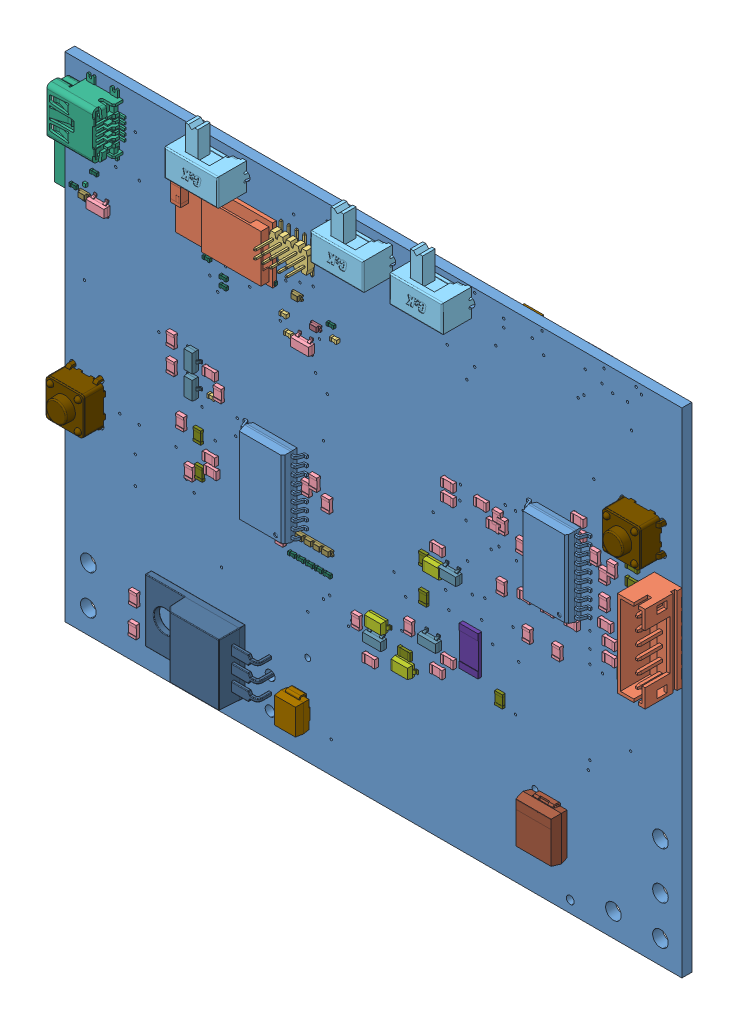
SolidWorks assembly test2, configuration Default. Lengths in mm.
Overall size (103.28 83.92 12.4).
129 component instances, 27 part files, 0 mates.
Components (placement in the parent):
- test2-1: test2 [Default] at origin size (100 80 1.6)
- Header Socket 2_0 6x-1: Header Socket 2_0 6x [Default] at (97.79 46.752 1.6) x (0 -1 0) z (-1 0 0) size (14 8 4.5)
- 0402c_2320560-1: 0402c_2320560 [Default] at (43.9928 61.722 1.6) size (1.15 0.6 0.55)
- 0402c_2320560-2: 0402c_2320560 [Default] at (35.814 61.214 1.6) size (1.15 0.6 0.55)
- 0402c_2320560-3: 0402c_2320560 [Default] at (36.5252 58.8264 1.6) size (1.15 0.6 0.55)
- 0402c_2320560-4: 0402c_2320560 [Default] at (95.123 74.295 0) x (-1 0 0) z (0 0 -1) size (1.15 0.6 0.55)
- 0402c_2320560-5: 0402c_2320560 [Default] at (98.552 77.724 0) x (-1 0 0) z (0 0 -1) size (1.15 0.6 0.55)
- 0402c_2320560-6: 0402c_2320560 [Default] at (78.994 77.978 0) x (-1 0 0) z (0 0 -1) size (1.15 0.6 0.55)
- 0402c_2320560-7: 0402c_2320560 [Default] at (89.916 75.438 0) x (-1 0 0) z (0 0 -1) size (1.15 0.6 0.55)
- 0402c_2320560-8: 0402c_2320560 [Default] at (78.74 74.93 0) x (-1 0 0) z (0 0 -1) size (1.15 0.6 0.55)
- 0402c_2320560-9: 0402c_2320560 [Default] at (90.805 78.232 0) x (-1 0 0) z (0 0 -1) size (1.15 0.6 0.55)
- 0402c_2320560-10: 0402c_2320560 [Default] at (68.58 76.962 0) x (-1 0 0) z (0 0 -1) size (1.15 0.6 0.55)
- 0402c_2320560-11: 0402c_2320560 [Default] at (68.58 78.232 0) x (-1 0 0) z (0 0 -1) size (1.15 0.6 0.55)
- 0402c_2320560-12: 0402c_2320560 [Default] at (68.58 75.438 0) x (-1 0 0) z (0 0 -1) size (1.15 0.6 0.55)
- 0402c_2320560-13: 0402c_2320560 [Default] at (94.488 60.198 0) x (-1 0 0) z (0 0 -1) size (1.15 0.6 0.55)
- 0402c_2320560-14: 0402c_2320560 [Default] at (24.13 43.815 1.6) size (1.15 0.6 0.55)
- 0805-1: 0805 [Default] at (89.0295 53.086 1.6) x (0 -1 0) z (-1 0 0) size (2.03 0.61 1.28)
- 0805-2: 0805 [Default] at (87.7545 49.53 1.6) x (0 1 0) z (1 0 0) size (2.03 0.61 1.28)
- 0805-3: 0805 [Default] at (87.7545 45.72 1.6) x (0 1 0) z (1 0 0) size (2.03 0.61 1.28)
- 0805-4: 0805 [Default] at (86.9696 43.7413 1.6) x (1 0 0) z (0 -1 0) size (2.03 0.61 1.28)
- 0805-5: 0805 [Default] at (87.63 41.5315 1.6) x (1 0 0) z (0 -1 0) size (2.03 0.61 1.28)
- 0805-6: 0805 [Default] at (86.2355 53.4416 1.6) x (0 -1 0) z (-1 0 0) size (2.03 0.61 1.28)
- 0805-7: 0805 [Default] at (77.724 41.2775 1.6) x (1 0 0) z (0 -1 0) size (2.03 0.61 1.28)
- 0805-8: 0805 [Default] at (73.914 41.2775 1.6) x (1 0 0) z (0 -1 0) size (2.03 0.61 1.28)
- 0805-9: 0805 [Default] at (81.534 41.2775 1.6) x (1 0 0) z (0 -1 0) size (2.03 0.61 1.28)
- 0805-10: 0805 [Default] at (82.55 54.2315 1.6) x (1 0 0) z (0 -1 0) size (2.03 0.61 1.28)
- 0805-11: 0805 [Default] at (74.2925 46.99 1.6) x (0 1 0) z (1 0 0) size (2.03 0.61 1.28)
- 0805-12: 0805 [Default] at (71.1225 41.656 1.6) x (0 -1 0) z (-1 0 0) size (2.03 0.61 1.28)
- 0805-13: 0805 [Default] at (50.8 19.6825 1.6) x (-1 0 0) z (0 1 0) size (2.03 0.61 1.28)
- 0805-14: 0805 [Default] at (63.5 25.9055 1.6) x (-1 0 0) z (0 1 0) size (2.03 0.61 1.28)
- 0805-15: 0805 [Default] at (61.722 23.6195 1.6) x (-1 0 0) z (0 1 0) size (2.03 0.61 1.28)
- 0805-16: 0805 [Default] at (40.7695 41.148 1.6) x (0 -1 0) z (-1 0 0) size (2.03 0.61 1.28)
- 0805-17: 0805 [Default] at (42.8015 39.116 1.6) x (0 -1 0) z (-1 0 0) size (2.03 0.61 1.28)
- 0805-18: 0805 [Default] at (11.5037 3.81 1.6) x (0 1 0) z (1 0 0) size (2.03 0.61 1.28)
- 0805-19: 0805 [Default] at (11.5545 8.2804 1.6) x (0 1 0) z (1 0 0) size (2.03 0.61 1.28)
- 1206-1: 1206 [Default] at (91.948 64.0055 0) x (1 0 0) z (0 1 0) size (3.05 0.61 1.53)
- JST SxB-PH-K-S (RIGHT ANGLE)-1: JST SxB-PH-K-S (RIGHT ANGLE) [Default] at (2.756 62.23 -2.4) x (0 1 0) z (-1 0 0) size (5.9 6.8 7.6)
- SOD123-1: SOD123 [Default] at (91.948 38.608 1.6) size (3.9 1.8 1.18)
- SOD123-2: SOD123 [Default] at (60.452 38.1 1.6) size (3.9 1.8 1.18)
- SOD123-3: SOD123 [Default] at (51.054 25.654 1.6) size (3.9 1.8 1.18)
- SOD123-4: SOD123 [Default] at (55.372 21.59 1.6) size (3.9 1.8 1.18)
- SOD 123-1: SOD 123 [Default] at (88.9 22.606 0) x (1 0 0) z (0 1 0) size (3.7 1.27 1.6)
- SOD 123-2: SOD 123 [Default] at (87.2744 22.606 0) x (1 0 0) z (0 1 0) size (3.7 1.27 1.6)
- SOD 123-3: SOD 123 [Default] at (92.0496 22.5552 0) x (1 0 0) z (0 1 0) size (3.7 1.27 1.6)
- SOD 123-4: SOD 123 [Default] at (90.424 22.5552 0) x (1 0 0) z (0 1 0) size (3.7 1.27 1.6)
- Diod SMD 10BF10-1: Diod SMD 10BF10 [Default] at (38.1 7.0104 2.83) x (0 1 0) z (1 0 0) size (5.3 2.43 3.6)
- TO-220-1: TO-220 [Default] at (33.274 6.604 1.6) x (0 1 0) z (1 0 0) size (10.16 7.2 19.49)
- SMC-1: SMC [Default] at (78.74 7.62 1.6) x (0 1 0) z (1 0 0) size (7.62 2.8 6.22)
- SMD_LED_0603-1: SMD_LED_0603 [Default] at (37.846 64.77 1.6) size (1.6 0.8 0.7)
- SMD_LED_0603-2: SMD_LED_0603 [Default] at (3.3274 61.722 1.6) size (1.6 0.8 0.7)
- STEP-WL-SMCW-0603-rev1-1: STEP-WL-SMCW-0603-rev1 [Default] at (40.894 61.976 1.6) size (1.6 0.8 0.7)
- SMD_LED_0603-3: SMD_LED_0603 [Default] at (37.084 31.4198 1.6) size (1.6 0.8 0.7)
- SMD_LED_0603-4: SMD_LED_0603 [Default] at (38.5064 31.4198 1.6) size (1.6 0.8 0.7)
- SMD_LED_0603-5: SMD_LED_0603 [Default] at (39.9796 31.4198 1.6) size (1.6 0.8 0.7)
- SMD_LED_0603-6: SMD_LED_0603 [Default] at (41.402 31.4198 1.6) size (1.6 0.8 0.7)
- SMD_LED_0603-7: SMD_LED_0603 [Default] at (42.8244 31.4198 1.6) size (1.6 0.8 0.7)
- SOT 23-1: SOT 23 [Default] at (62.992 38.354 2.15) x (1 0 0) z (0 -1 0) size (3 1.1 2.5)
- SOT 23-2: SOT 23 [Default] at (21.082 47.625 2.15) x (0 1 0) z (1 0 0) size (3 1.1 2.5)
- SOT 23-3: SOT 23 [Default] at (59.69 27.305 2.15) x (1 0 0) z (0 -1 0) size (3 1.1 2.5)
- SOT 23-4: SOT 23 [Default] at (21.082 43.815 2.15) x (0 1 0) z (1 0 0) size (3 1.1 2.5)
- SOT 23-5: SOT 23 [Default] at (50.8 23.114 2.15) x (1 0 0) z (0 -1 0) size (3 1.1 2.5)
- 0402r_1430758-1: 0402r_1430758 [Default] at (25.9588 61.3664 1.6) size (1.15 0.55 0.4)
- 0402r_1430758-2: 0402r_1430758 [Default] at (25.9588 60.0964 1.6) size (1.15 0.55 0.4)
- 0402r_1430758-3: 0402r_1430758 [Default] at (4.9784 65.6082 1.6) size (1.15 0.55 0.4)
- 0402r_1430758-4: 0402r_1430758 [Default] at (1.6256 62.1284 1.6) size (1.15 0.55 0.4)
- 0402r_1430758-5: 0402r_1430758 [Default] at (33.909 64.77 1.6) size (1.15 0.55 0.4)
- 0402r_1430758-6: 0402r_1430758 [Default] at (23.241 62.738 1.6) size (1.15 0.55 0.4)
- 0402r_1430758-7: 0402r_1430758 [Default] at (89.281 78.232 0) x (-1 0 0) z (0 0 -1) size (1.15 0.55 0.4)
- 0402r_1430758-8: 0402r_1430758 [Default] at (43.3324 63.4238 1.6) size (1.15 0.55 0.4)
- 0402r_1430758-9: 0402r_1430758 [Default] at (93.218 60.198 0) x (-1 0 0) z (0 0 -1) size (1.15 0.55 0.4)
- 0402r_1430758-10: 0402r_1430758 [Default] at (42.8244 28.1178 1.6) size (1.15 0.55 0.4)
- 0402r_1430758-11: 0402r_1430758 [Default] at (41.402 28.1178 1.6) size (1.15 0.55 0.4)
- 0402r_1430758-12: 0402r_1430758 [Default] at (39.9796 28.1178 1.6) size (1.15 0.55 0.4)
- 0402r_1430758-13: 0402r_1430758 [Default] at (37.084 28.1178 1.6) size (1.15 0.55 0.4)
- 0402r_1430758-14: 0402r_1430758 [Default] at (38.5064 28.1178 1.6) size (1.15 0.55 0.4)
- Resistor 0805-1: Resistor 0805 [Default] at (92.202 54.102 1.63) x (1 0 0) z (0 -1 0) size (2 0.46 1.26)
- Resistor 0805-2: Resistor 0805 [Default] at (92.202 51.562 1.63) x (1 0 0) z (0 -1 0) size (2 0.46 1.26)
- Resistor 0805-3: Resistor 0805 [Default] at (92.202 49.022 1.63) x (1 0 0) z (0 -1 0) size (2 0.46 1.26)
- Resistor 0805-4: Resistor 0805 [Default] at (92.202 46.482 1.63) x (1 0 0) z (0 -1 0) size (2 0.46 1.26)
- Resistor 0805-5: Resistor 0805 [Default] at (92.202 43.942 1.63) x (1 0 0) z (0 -1 0) size (2 0.46 1.26)
- Resistor 0805-6: Resistor 0805 [Default] at (92.202 41.402 1.63) x (1 0 0) z (0 -1 0) size (2 0.46 1.26)
- Resistor 0805-7: Resistor 0805 [Default] at (70.739 24.638 1.63) x (0 1 0) z (1 0 0) size (2 0.46 1.26)
- Resistor 0805-8: Resistor 0805 [Default] at (58.42 32.766 1.63) x (0 -1 0) z (-1 0 0) size (2 0.46 1.26)
- Resistor 0805-9: Resistor 0805 [Default] at (58.42 38.1 1.63) x (0 -1 0) z (-1 0 0) size (2 0.46 1.26)
- Resistor 0805-10: Resistor 0805 [Default] at (55.372 23.368 1.63) x (1 0 0) z (0 -1 0) size (2 0.46 1.26)
- Resistor 0805-11: Resistor 0805 [Default] at (34.29 34.671 -0.03) x (-1 0 0) z (0 -1 0) size (2 0.46 1.26)
- Resistor 0805-12: Resistor 0805 [Default] at (22.098 32.131 1.63) x (0 1 0) z (1 0 0) size (2 0.46 1.26)
- Resistor 0805-13: Resistor 0805 [Default] at (21.844 37.211 1.63) x (0 -1 0) z (-1 0 0) size (2 0.46 1.26)
- 0805-20: 0805 [Default] at (91.948 37.2135 1.6) x (1 0 0) z (0 -1 0) size (2.03 0.61 1.28)
- 0805-21: 0805 [Default] at (87.63 39.2455 1.6) x (1 0 0) z (0 -1 0) size (2.03 0.61 1.28)
- 0805-22: 0805 [Default] at (75.3135 37.084 1.6) x (0 -1 0) z (-1 0 0) size (2.03 0.61 1.28)
- 0805-23: 0805 [Default] at (80.1395 37.084 1.6) x (0 -1 0) z (-1 0 0) size (2.03 0.61 1.28)
- 0805-24: 0805 [Default] at (82.55 56.2635 1.6) x (1 0 0) z (0 -1 0) size (2.03 0.61 1.28)
- 0805-25: 0805 [Default] at (61.722 40.7645 1.6) x (-1 0 0) z (0 1 0) size (2.03 0.61 1.28)
- 0805-26: 0805 [Default] at (70.4875 51.054 1.6) x (0 -1 0) z (-1 0 0) size (2.03 0.61 1.28)
- 0805-27: 0805 [Default] at (71.2445 48.26 1.6) x (0 1 0) z (1 0 0) size (2.03 0.61 1.28)
- 0805-28: 0805 [Default] at (92.456 54.7395 0) x (-1 0 0) z (0 -1 0) size (2.03 0.61 1.28)
- 0805-29: 0805 [Default] at (56.1315 26.543 1.6) x (0 1 0) z (1 0 0) size (2.03 0.61 1.28)
- 0805-30: 0805 [Default] at (47.6225 23.114 1.6) x (0 1 0) z (1 0 0) size (2.03 0.61 1.28)
- 0805-31: 0805 [Default] at (39.4945 37.719 1.6) x (0 1 0) z (1 0 0) size (2.03 0.61 1.28)
- 0805-32: 0805 [Default] at (24.892 46.9875 1.6) x (-1 0 0) z (0 1 0) size (2.03 0.61 1.28)
- 0805-33: 0805 [Default] at (25.2705 43.815 1.6) x (0 1 0) z (1 0 0) size (2.03 0.61 1.28)
- 0805-34: 0805 [Default] at (17.6505 47.625 1.6) x (0 1 0) z (1 0 0) size (2.03 0.61 1.28)
- 0805-35: 0805 [Default] at (17.6505 43.815 1.6) x (0 1 0) z (1 0 0) size (2.03 0.61 1.28)
- 0805-36: 0805 [Default] at (35.3085 30.734 1.6) x (0 -1 0) z (-1 0 0) size (2.03 0.61 1.28)
- 0805-37: 0805 [Default] at (25.146 33.2715 1.6) x (-1 0 0) z (0 1 0) size (2.03 0.61 1.28)
- 0805-38: 0805 [Default] at (24.892 35.0495 1.6) x (-1 0 0) z (0 1 0) size (2.03 0.61 1.28)
- 0805-39: 0805 [Default] at (20.5765 32.512 1.6) x (0 -1 0) z (-1 0 0) size (2.03 0.61 1.28)
- 0805-40: 0805 [Default] at (19.1745 36.83 1.6) x (0 1 0) z (1 0 0) size (2.03 0.61 1.28)
- 0805-41: 0805 [Default] at (66.802 50.6755 1.6) x (1 0 0) z (0 -1 0) size (2.03 0.61 1.28)
- 0805-42: 0805 [Default] at (68.834 48.6435 1.6) x (1 0 0) z (0 -1 0) size (2.03 0.61 1.28)
- 0805-43: 0805 [Default] at (61.468 48.6435 1.6) x (1 0 0) z (0 -1 0) size (2.03 0.61 1.28)
- 0805-44: 0805 [Default] at (61.468 50.6755 1.6) x (1 0 0) z (0 -1 0) size (2.03 0.61 1.28)
- 2512-1: 2512 [Default] at (66.0425 26.035 1.6) x (0 1 0) z (1 0 0) size (6.35 0.61 3.05)
- Tact DIP 6x6-1: Tact DIP 6x6 [Default] at (93.726 60.198 1.6) x (1 0 0) z (0 -1 0) size (6.85 7 6)
- Tact DIP 6x6-2: Tact DIP 6x6 [Default] at (3.556 33.655 1.6) x (0 -1 0) z (-1 0 0) size (6.85 7 6)
- SO_IC20-1: SO_IC20 [Default] at (80.264 49.022 3) x (0 -1 0) z (-1 0 0) size (12.8 2.5 10.34)
- BLE113 v0-1: BLE113 v0 [Default] at (26.416 68.834 1.6) size (15.73 9.15 1.91)
- AmphenolConnHeader-1: AmphenolConnHeader [Default] at (35.179 71.374 1.6) x (1 0 0) z (0 -1 0) size (6.25 4.5 5.5)
- SOT 23-5-1: SOT 23-5 [Default] at (39.116 58.674 2.15) x (1 0 0) z (0 -1 0) size (3 1.1 2.5)
- CKN9559-ND-1: CKN9559-ND [Default] at (25.146 77.216 1.6) x (-1 0 0) z (0 0 -1) size (8.61 8.41 7.51)
- CKN9559-ND-2: CKN9559-ND [Default] at (48.768 77.216 1.6) x (-1 0 0) z (0 0 -1) size (8.61 8.41 7.51)
- CKN9559-ND-3: CKN9559-ND [Default] at (61.595 77.724 1.6) x (-1 0 0) z (0 0 -1) size (8.61 8.41 7.51)
- USB_Mini_B_SMD_buchse-1: USB_Mini_B_SMD_buchse [Standard] at (0.45 74.168 3.61) x (0 -1 0) z (-1 0 0) size (10 3.96 8.9)
- KXCJ9_KXCJ9-1: KXCJ9_KXCJ9 [Default] at (95.758 77.47 0) x (-1 0 0) z (0 0 -1) size (3.05 3.02 1)
- FXAS21002_FXAS21002-1: FXAS21002_FXAS21002 [Default] at (84.201 76.962 0) x (-1 0 0) z (0 0 -1) size (4.13 4.06 1)
- SO_IC20-2: SO_IC20 [Default] at (34.29 37.211 3) x (0 -1 0) z (-1 0 0) size (12.8 2.5 10.34)
- SOT 23-5-2: SOT 23-5 [Default] at (5.969 61.468 2.15) x (1 0 0) z (0 -1 0) size (3 1.1 2.5)
- MLP3115A2_MLP3115A2-1: MLP3115A2_MLP3115A2 [Default] at (73.406 76.708 0) x (-1 0 0) z (0 0 -1) size (3.13 5.06 1)
